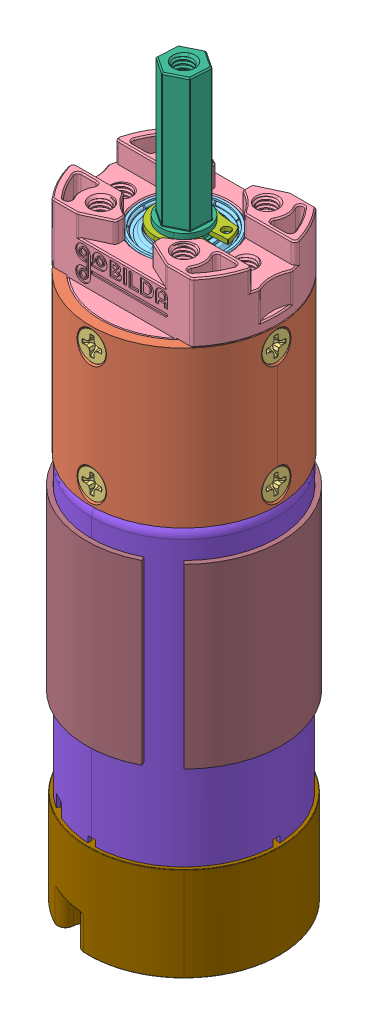
SolidWorks assembly Rex shaft 435rpm motor, configuration Default. Lengths in mm.
Overall size (52.29 140.05 52.29).
30 component instances, 15 part files, 0 mates.
Components (placement in the parent):
- 5203-2402-0014 assembly.STEP-1: 5203-2402-0014 assembly.STEP [Default] at origin size (52.29 140.05 52.29)
  - 5103-2402-0014 Simple.STEP-1: 5103-2402-0014 Simple.STEP [Default] at (21.5499 39.1 -25.8711) size (36 65.1 35.97)
    - 5103 Gearbox Base.STEP-1: 5103 Gearbox Base.STEP [Default] at (-58.7206 21.0354 14.7927) size (31.91 5.69 31.91)
    - 5103 Gearbox Barrel (2 stage, simple)_Gear Blank.STEP-1: 5103 Gearbox Barrel (2 stage, simple)_Gear Blank.STEP [Default] at (-58.7206 64.0354 14.7927) x (1 0 0) z (0 -1 0) size (35.97 35.97 30)
    - 5103 Gearbox Barrel Screw (M3 x 8mm length Flat Head)_92010A118.STEP-1: 5103 Gearbox Barrel Screw (M3 x 8mm length Flat Head)_92010A118.STEP [Default] at (-58.7206 24.5354 30.8757) x (0.002439 -0.999997 0) z (0 0 1) size (5.46 5.46 8)
    - 5103 Gearbox Barrel Screw (M3 x 8mm length Flat Head)_92010A118.STEP-2: 5103 Gearbox Barrel Screw (M3 x 8mm length Flat Head)_92010A118.STEP [Default] at (-58.7206 47.5354 30.8757) x (-0.002439 -0.999997 0) z (0 0 1) size (5.46 5.46 8)
    - 5103 Gearbox Barrel Screw (M3 x 8mm length Flat Head)_92010A118.STEP-3: 5103 Gearbox Barrel Screw (M3 x 8mm length Flat Head)_92010A118.STEP [Default] at (-42.6376 24.5354 14.7927) x (0 -0.999997 -0.002439) z (1 0 0) size (5.46 5.46 8)
    - 5103 Gearbox Barrel Screw (M3 x 8mm length Flat Head)_92010A118.STEP-4: 5103 Gearbox Barrel Screw (M3 x 8mm length Flat Head)_92010A118.STEP [Default] at (-58.7206 24.5354 -1.2903) x (-0.002439 -0.999997 0) z (0 0 -1) size (5.46 5.46 8)
    - 5103 Gearbox Barrel Screw (M3 x 8mm length Flat Head)_92010A118.STEP-5: 5103 Gearbox Barrel Screw (M3 x 8mm length Flat Head)_92010A118.STEP [Default] at (-74.8037 24.5354 14.7927) x (0 -0.999997 0.002439) z (-1 0 0) size (5.46 5.46 8)
    - 5103 Gearbox Barrel Screw (M3 x 8mm length Flat Head)_92010A118.STEP-6: 5103 Gearbox Barrel Screw (M3 x 8mm length Flat Head)_92010A118.STEP [Default] at (-42.6376 47.5354 14.7927) x (0 -0.999997 0.002439) z (1 0 0) size (5.46 5.46 8)
    - 5103 Gearbox Barrel Screw (M3 x 8mm length Flat Head)_92010A118.STEP-7: 5103 Gearbox Barrel Screw (M3 x 8mm length Flat Head)_92010A118.STEP [Default] at (-58.7206 47.5354 -1.2903) x (0.002439 -0.999997 0) z (0 0 -1) size (5.46 5.46 8)
    - 5103 Gearbox Barrel Screw (M3 x 8mm length Flat Head)_92010A118.STEP-8: 5103 Gearbox Barrel Screw (M3 x 8mm length Flat Head)_92010A118.STEP [Default] at (-74.8037 47.5354 14.7927) x (0 -0.999997 -0.002439) z (-1 0 0) size (5.46 5.46 8)
    - 5103 Gearbox Face.STEP-1: 5103 Gearbox Face.STEP [Default] at (-58.7206 45.5354 14.7927) size (36 17.1 31.91)
    - 5103 Gearbox Bearing.STEP-1: 5103 Gearbox Bearing.STEP [Default] at (-58.7206 53.6354 14.7927) size (17 5 17)
    - 5103 Gearbox Bearing.STEP-2: 5103 Gearbox Bearing.STEP [Default] at (-58.7206 45.5354 14.7927) size (17 5 17)
    - 5103 Gearbox Shaft (23.5mm Length, Simple).STEP-1: 5103 Gearbox Shaft (23.5mm Length, Simple).STEP [Default] at (-58.7206 42.1754 14.7927) x (0.894773 0 -0.44652) z (0.44652 0 0.894773) size (8.97 40.6 8.97)
    - 5103 Gearbox Snap Ring.STEP-1: 5103 Gearbox Snap Ring.STEP [Default] at (-58.7206 58.7104 14.7927) x (0 1 0) z (0 0 1) size (0.85 13.06 10.66)
  - 5000-0002-0001 body.step-1: 5000-0002-0001 body.step [Default] at (-37.1707 3.4854 -11.0784) size (35.61 61.8 35.61)
  - 5000-0001-0001 encoder cap.STEP-1: 5000-0001-0001 encoder cap.STEP [Default] at (-37.1707 -14.6146 -11.0784) x (0.707107 0 -0.707107) z (0 -1 0) size (36.9 36.9 18.3)
  - 5000-0001-0001 encoder cap screw_90190A075.STEP-1: 5000-0001-0001 encoder cap screw_90190A075.STEP [Default] at (-33.0775 -8.1646 -26.1474) x (0.882398 0 0.470504) z (0 -1 0) size (3.33 3.33 7.86)
  - 5000-0001-0001 encoder pin housing.STEP-1: 5000-0001-0001 encoder pin housing.STEP [Default] at (-44.0085 -0.9746 -21.9467) x (0.707107 0 -0.707107) z (-0.707107 0 -0.707107) size (12.3 7.19 6.3)
  - 5000-0001-0001 encoder pins_MalePinHeader_1X2.STEP-1: 5000-0001-0001 encoder pins_MalePinHeader_1X2.STEP [Default] at (-43.4569 1.2544 -23.1912) x (0.707107 0 -0.707107) z (0 -1 0) size (3.18 0.64 4.27)
  - 5000-0001-0001 motor shield.STEP-1: 5000-0001-0001 motor shield.STEP [Default] at (-37.1707 54.6354 -11.0784) x (0.808104 0 -0.58904) z (0 -1 0) size (37.5 37.27 34.15)
  - 5000-0001-0001 encoder cap screw_90190A075.STEP-2: 5000-0001-0001 encoder cap screw_90190A075.STEP [Default] at (-41.264 -8.1646 3.9905) x (0.882398 0 0.470504) z (0 -1 0) size (3.33 3.33 7.86)
  - 5000-0001-0001 encoder pins_MalePinHeader_1X2.STEP-2: 5000-0001-0001 encoder pins_MalePinHeader_1X2.STEP [Default] at (-47.049 1.2544 -19.5991) x (0.707107 0 -0.707107) z (0 -1 0) size (3.18 0.64 4.27)
  - 5000-0002-0117 motor shaft.STEP-1: 5000-0002-0117 motor shaft.STEP [Default] at (-37.1707 59.4854 -11.0784) size (3.26 12.45 3.14)
  - 5103 Gearbox Base Mounting Screw M3 x 5mm length SHCS)_91290A110.STEP-1: 5103 Gearbox Base Mounting Screw M3 x 5mm length SHCS)_91290A110.STEP [Default] at (-46.0096 57.2554 -2.2396) x (0.056382 0 0.998409) z (0 -1 0) size (5.5 5.5 8.01)
  - 5103 Gearbox Base Mounting Screw M3 x 5mm length SHCS)_91290A110.STEP-2: 5103 Gearbox Base Mounting Screw M3 x 5mm length SHCS)_91290A110.STEP [Default] at (-28.3319 57.2554 -2.2396) x (0.998409 0 -0.056382) z (0 -1 0) size (5.5 5.5 8.01)
  - 5103 Gearbox Base Mounting Screw M3 x 5mm length SHCS)_91290A110.STEP-3: 5103 Gearbox Base Mounting Screw M3 x 5mm length SHCS)_91290A110.STEP [Default] at (-28.3319 57.2554 -19.9173) x (-0.056382 0 -0.998409) z (0 -1 0) size (5.5 5.5 8.01)
  - 5103 Gearbox Base Mounting Screw M3 x 5mm length SHCS)_91290A110.STEP-4: 5103 Gearbox Base Mounting Screw M3 x 5mm length SHCS)_91290A110.STEP [Default] at (-46.0096 57.2554 -19.9173) x (-0.998409 0 0.056382) z (0 -1 0) size (5.5 5.5 8.01)
